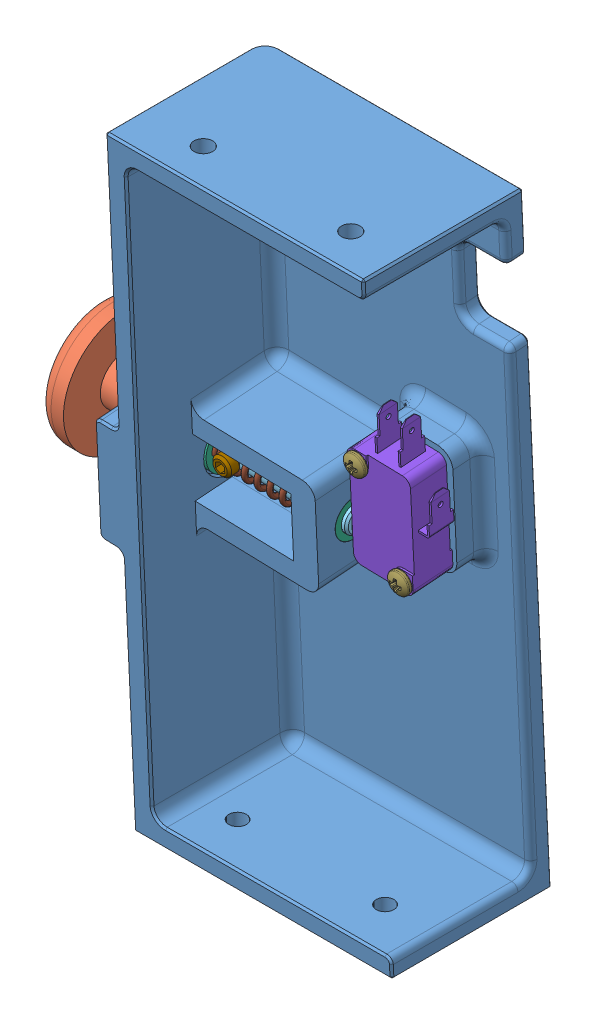
SolidWorks assembly DISP Button Assembly, configuration Default. Lengths in mm.
Overall size (99.96 165.48 53.92).
18 component instances, 13 part files, 0 mates.
Components (placement in the parent):
- DISP_Button_Base-1: DISP_Button_Base [Default] at origin size (75.67 165.48 53.92)
- DISP_Button_Head-1: DISP_Button_Head [Default] at (-19.5078 -24.0015 47.9254) x (0.999995 -0.003076 -0.000207) z (0.000231 0.007723 0.99997) size (16.73 32.11 31.89)
  - DISP_Button_Head-1: DISP_Button_Head [Default] at origin size (16.73 32.11 31.89)
  - 90480A009 - NUT, 8-32, STEEL-1: 90480A009 - NUT, 8-32, STEEL [90480A009] at (326.9082 6184.0708 3260.9167) x (-0.026875 -0.996836 -0.074802) z (0.999639 -0.0268 -0.002011) size (8.73 3.79 10.08)
  - 92311A189 - SCREW, SET, 8-32 X .1875, CUP POINT, HEX DRIVE, 18-8-1: 92311A189 - SCREW, SET, 8-32 X .1875, CUP POINT, HEX DRIVE, 18-8 [92311A189] at (326.9082 6184.037 3261.3663) x (-0.906998 -0.419955 -0.031513) z (0 0.074829 -0.997196) size (4.2 4.28 5.07)
- DISP Button Shaft-1: DISP Button Shaft [Default] at origin size (63.63 8.22 6.48)
- 6338K411-1: 6338K411 [Default] at (351.2767 6182.8913 3267.1365) x (0.029957 0.997297 0.067095) z (0 -0.067125 0.997745) size (12.7 6.35 12.7)
- 6338K411-2: 6338K411 [Default] at (376.6653 6182.1321 3267.0854) x (-0.029957 -0.997297 -0.067095) z (0 -0.067125 0.997745) size (12.7 6.35 12.7)
- 93365A120_BRASS HEAT-SET INSERT FOR PLASTICS_4-40-1: 93365A120_BRASS HEAT-SET INSERT FOR PLASTICS_4-40 [93365A120] at (400.6055 6180.0226 3261.8384) x (1 -0.000017 0.000231) z (0 -0.997197 -0.074822) size (4.37 3.82 4.37)
- 93365A120_BRASS HEAT-SET INSERT FOR PLASTICS_4-40-2: 93365A120_BRASS HEAT-SET INSERT FOR PLASTICS_4-40 [93365A120] at (390.8581 6202.36 3263.5122) x (1 -0.000017 0.000231) z (0 -0.997197 -0.074822) size (4.37 3.82 4.37)
- 7779K61-1: 7779K61 [Default] at (395.7083 6190.7842 3267.8142) x (0.026177 0.996855 0.074802) z (-0.000231 -0.074822 0.997197) size (37.78 21.56 10.31)
- 9414T6-1: 9414T6 [Default] at (354.8819 6182.7835 3267.1293) x (0.029957 0.997297 0.067095) z (0.999551 -0.029889 -0.002011) size (4.83 3.17 4.83)
- 90131A102-1: 90131A102 [Default] at (340.239 6183.2214 3267.1587) x (0 -0.067125 0.997745) z (0.999551 -0.029889 -0.002011) size (19.05 19.05 3.56)
- 9657K305-1: 9657K305 [Default] at (376.6653 6182.1134 3267.3642) x (0 -0.067125 0.997745) z (0.999551 -0.029889 -0.002011) size (9.42 9.49 26.7)
- 91249A115-1: 91249A115 [Default] at (390.8594 6202.7764 3257.9628) x (0.999657 -0.026121 -0.001728) z (-0.000231 -0.074822 0.997197) size (23.09 11.07 22.41)
- 91249A115-2: 91249A115 [Default] at (400.5935 6180.3766 3256.2843) x (0.999657 -0.026121 -0.001728) z (-0.000231 -0.074822 0.997197) size (23.09 11.07 22.41)
- 91841A009 (2)-1: 91841A009 (2) [Default] at (364.6021 6260.7825 3287.5106) x (1 0 0) z (0 0 1) size (8.73 4.11 10.08)
- 91841A009 (2)-2: 91841A009 (2) [Default] at (402.7022 6260.7825 3287.5106) x (1 0 0) z (0 0 1) size (8.73 4.11 10.08)
